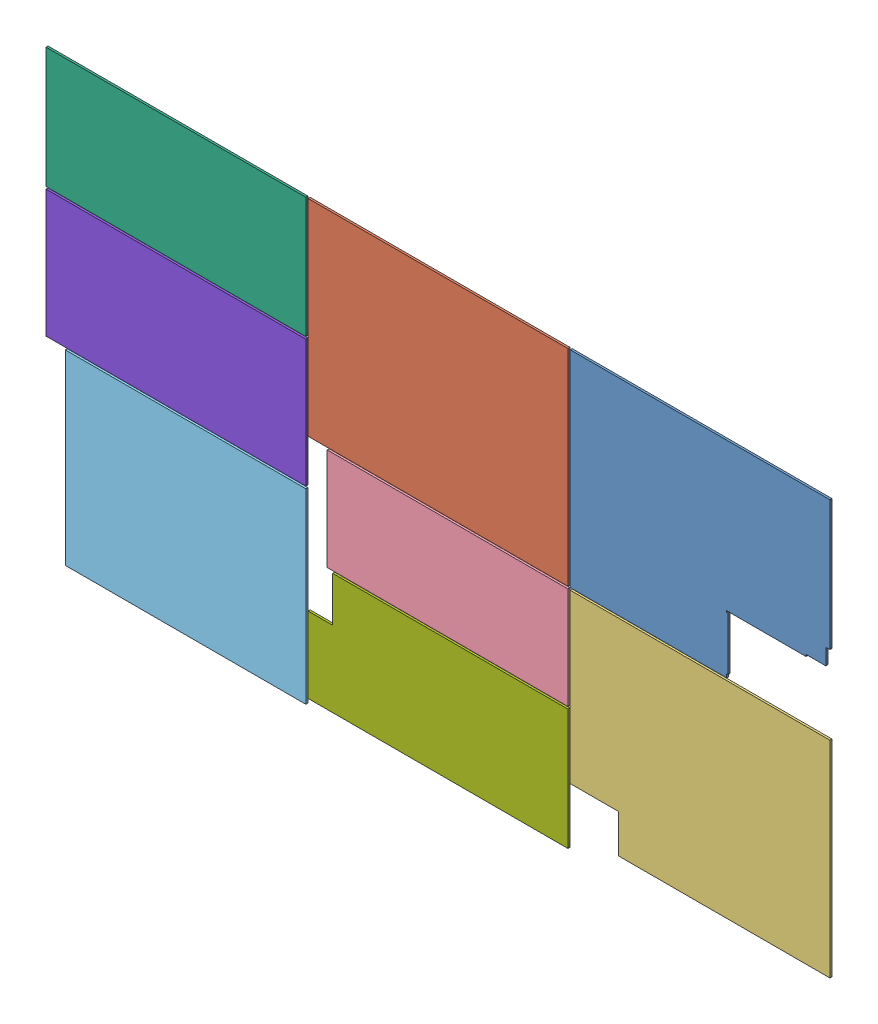
SolidWorks assembly Assem1, configuration Default. Lengths in mm.
Overall size (1747 978.75 4.5).
8 component instances, 8 part files, 21 mates.
Components (placement in the parent):
- Acrylic_or_Polycarbonate_Backside_Panel-1: Acrylic_or_Polycarbonate_Backside_Panel [Default] at origin size (579 459 4.5)
- Acrylic_or_Polycarbonate_Leftside_Panel-1: Acrylic_or_Polycarbonate_Leftside_Panel [Default] at (-584 0 0) size (579 459 4.5)
- Acrylic_or_Polycarbonate_Rightside_Panel-1: Acrylic_or_Polycarbonate_Rightside_Panel [Default] at (0 -464 0) size (579 459 4.5)
- Acrylic_or_Polycarbonate_Cover_Door-1: Acrylic_or_Polycarbonate_Cover_Door [Default] at (-562.75 -348 0) size (536.5 227 4.5)
- Acrylic_or_Polycarbonate_Door_Window-1: Acrylic_or_Polycarbonate_Door_Window [Default] at (-1146.5 -541.25 0) size (536 416 4.5)
- Acrylic_or_Polycarbonate_Left_Front_Back_Cover-1: Acrylic_or_Polycarbonate_Left_Front_Back_Cover [Default] at (-1168 95 0) size (579 269 4.5)
- Acrylic_or_Polycarbonate_Right_Cover-1: Acrylic_or_Polycarbonate_Right_Cover [Default] at (-584 -601 0) size (579 269 4.5)
- Acrylic_or_Polycarbonate_SplitTop_Cover-1: Acrylic_or_Polycarbonate_SplitTop_Cover [Default] at (-1168 -186.375 0) size (579 283.75 4.5)
Mates (geometry in assembly coordinates):
- Coincident7: coincident aligned: plane of Acrylic_or_Polycarbonate_Backside_Panel-1 through (0 0 2.2479) normal (0 0 1); plane of Acrylic_or_Polycarbonate_Rightside_Panel-1 through (0 -464 2.2479) normal (0 0 1)
- Coincident8: coincident aligned: plane of Acrylic_or_Polycarbonate_Backside_Panel-1 through (0 0 2.2479) normal (0 0 1); plane of Acrylic_or_Polycarbonate_Leftside_Panel-1 through (-584 0 2.2479) normal (0 0 1)
- Coincident9: coincident aligned: plane of Acrylic_or_Polycarbonate_Backside_Panel-1 through (0 0 2.2479) normal (0 0 1); plane of Acrylic_or_Polycarbonate_Cover_Door-1 through (-562.75 -348 2.2479) normal (0 0 1)
- Coincident10: coincident aligned: plane of Acrylic_or_Polycarbonate_Backside_Panel-1 through (0 0 2.2479) normal (0 0 1); plane of Acrylic_or_Polycarbonate_Right_Cover-1 through (-584 -601 2.2479) normal (0 0 1)
- Coincident11: coincident aligned: plane of Acrylic_or_Polycarbonate_Backside_Panel-1 through (0 0 2.2479) normal (0 0 1); plane of Acrylic_or_Polycarbonate_Door_Window-1 through (-1146.5 -595.5401 2.2479) normal (0 0 1)
- Coincident12: coincident aligned: plane of Acrylic_or_Polycarbonate_Backside_Panel-1 through (0 0 2.2479) normal (0 0 1); plane of Acrylic_or_Polycarbonate_SplitTop_Cover-1 through (-1168 -186.375 2.2479) normal (0 0 1)
- Coincident13: coincident aligned: plane of Acrylic_or_Polycarbonate_Backside_Panel-1 through (0 0 2.2479) normal (0 0 1); plane of Acrylic_or_Polycarbonate_Left_Front_Back_Cover-1 through (-1168 95 2.2479) normal (0 0 1)
- Coincident14: coincident aligned: plane of Acrylic_or_Polycarbonate_Backside_Panel-1 through (-289.5 -229.5 2.2479) normal (-1 0 0); plane of Acrylic_or_Polycarbonate_Rightside_Panel-1 through (-289.5 -693.5 2.2479) normal (-1 0 0)
- Distance3: distance = 5 mm anti-aligned: plane of Acrylic_or_Polycarbonate_Backside_Panel-1 through (-289.5 -229.5 2.2479) normal (-1 0 0); plane of Acrylic_or_Polycarbonate_Leftside_Panel-1 through (-294.5 -229.5 2.2479) normal (1 0 0)
- Coincident16: coincident aligned: plane of Acrylic_or_Polycarbonate_Leftside_Panel-1 through (-294.5 -229.5 2.2479) normal (1 0 0); plane of Acrylic_or_Polycarbonate_Cover_Door-1 through (-294.5 -461.5 2.2479) normal (1 0 0)
- Coincident17: coincident aligned: plane of Acrylic_or_Polycarbonate_Leftside_Panel-1 through (-294.5 -229.5 2.2479) normal (1 0 0); plane of Acrylic_or_Polycarbonate_Right_Cover-1 through (-294.5 -735.5 2.2479) normal (1 0 0)
- Distance4: distance = 5 mm anti-aligned: plane of Acrylic_or_Polycarbonate_Backside_Panel-1 through (-289.5 -229.5 2.2479) normal (0 -1 0); plane of Acrylic_or_Polycarbonate_Rightside_Panel-1 through (-289.5 -234.5 2.2479) normal (0 1 0)
- Coincident22: coincident aligned: plane of Acrylic_or_Polycarbonate_Backside_Panel-1 through (-289.5 229.5 2.2479) normal (0 1 0); plane of Acrylic_or_Polycarbonate_Leftside_Panel-1 through (-873.5 229.5 2.2479) normal (0 1 0)
- Coincident23: coincident aligned: plane of Acrylic_or_Polycarbonate_Rightside_Panel-1 through (-289.5 -234.5 2.2479) normal (0 1 0); plane of Acrylic_or_Polycarbonate_Cover_Door-1 through (-831 -234.5 2.2479) normal (0 1 0)
- Distance8: distance = 5 mm anti-aligned: plane of Acrylic_or_Polycarbonate_Cover_Door-1 through (-831 -461.5 2.2479) normal (0 -1 0); plane of Acrylic_or_Polycarbonate_Right_Cover-1 through (-873.5 -466.5 2.2479) normal (0 1 0)
- Coincident25: coincident aligned: plane of Acrylic_or_Polycarbonate_Leftside_Panel-1 through (-873.5 229.5 2.2479) normal (0 1 0); plane of Acrylic_or_Polycarbonate_Left_Front_Back_Cover-1 through (-1457.5 229.5 2.2479) normal (0 1 0)
- Distance9: distance = 5 mm anti-aligned: plane of Acrylic_or_Polycarbonate_Leftside_Panel-1 through (-873.5 -229.5 2.2479) normal (-1 0 0); plane of Acrylic_or_Polycarbonate_Left_Front_Back_Cover-1 through (-878.5 -39.5 2.2479) normal (1 0 0)
- Coincident27: coincident aligned: plane of Acrylic_or_Polycarbonate_Left_Front_Back_Cover-1 through (-878.5 -39.5 2.2479) normal (1 0 0); plane of Acrylic_or_Polycarbonate_SplitTop_Cover-1 through (-878.5 -328.25 2.2479) normal (1 0 0)
- Coincident28: coincident aligned: plane of Acrylic_or_Polycarbonate_Left_Front_Back_Cover-1 through (-878.5 -39.5 2.2479) normal (1 0 0); plane of Acrylic_or_Polycarbonate_Door_Window-1 through (-878.5 -749.25 2.2479) normal (1 0 0)
- Distance10: distance = 5 mm anti-aligned: plane of Acrylic_or_Polycarbonate_Left_Front_Back_Cover-1 through (-1457.5 -39.5 2.2479) normal (0 -1 0); plane of Acrylic_or_Polycarbonate_SplitTop_Cover-1 through (-1457.5 -44.5 2.2479) normal (0 1 0)
- Distance11: distance = 5 mm anti-aligned: plane of Acrylic_or_Polycarbonate_Door_Window-1 through (-1414.5 -333.25 2.2479) normal (0 1 0); plane of Acrylic_or_Polycarbonate_SplitTop_Cover-1 through (-1457.5 -328.25 2.2479) normal (0 -1 0)
